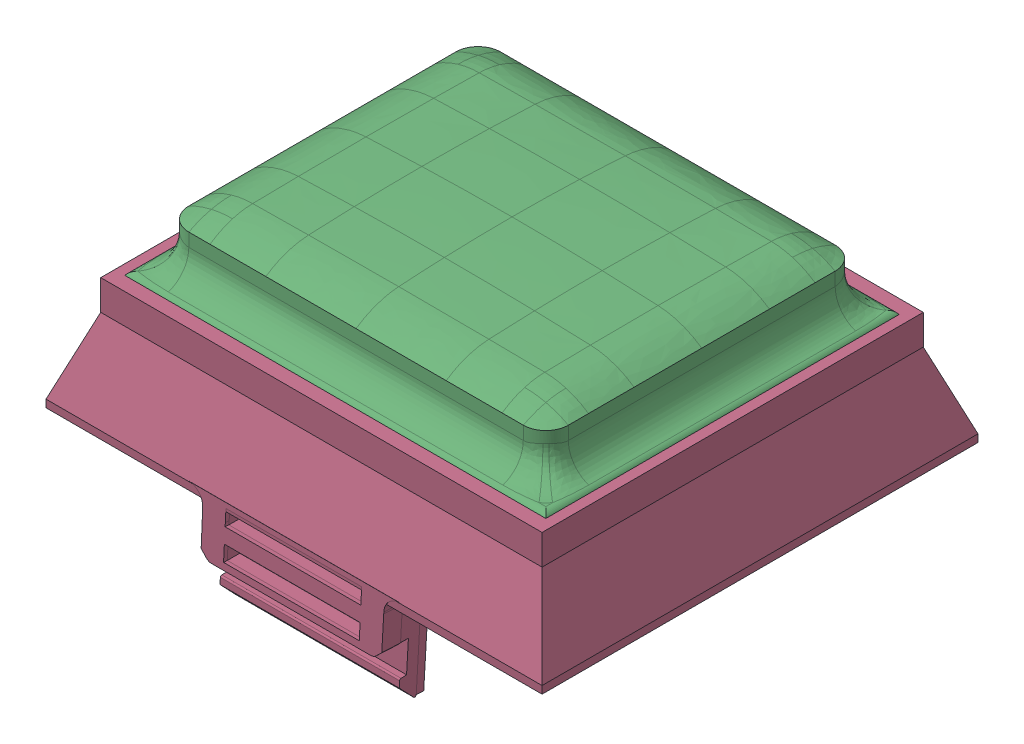
SolidWorks assembly BoardALL, configuration 默认. Lengths in mm.
Overall size (33 18.3 29.5).
5 component instances, 5 part files, 13 mates.
Components (placement in the parent):
- Boardlensall-1: Boardlensall [默认] at origin size (28.33 2.18 23.83)
- BoardInsideSkin-1: BoardInsideSkin [默认] at (0.0001 0 0.2499) size (23.8 5.48 19.29)
- BoardTopskin-1: BoardTopskin [默认] at (0.0001 2 0.2499) size (28.02 6.25 23.52)
- BoardSupportBase-2: BoardSupportBase [默认] at origin size (33 14.05 29.5)
- chessboard-1: chessboard [默认] at (-4.7946 23.7 -14.5409) x (1 0 0) z (0 -1 0) size (22.5 16.35 0.4)
Mates (geometry in assembly coordinates):
- 同心2: concentric anti-aligned: cylinder of BoardInsideSkin-1 through (10.8751 17.7531 8.6249) axis (0 1 0) radius 0.7; cylinder of Board3Con1612611OriginalSkin_TOP-1 through (10.8751 24 8.6249) axis (0 -1 0) radius 0.7
- 同心3: concentric anti-aligned: cylinder of BoardInsideSkin-1 through (10.8751 17.7531 -9.1251) axis (0 1 0) radius 0.7; cylinder of Board3Con1612611OriginalSkin_TOP-1 through (10.8751 24 -9.1251) axis (0 -1 0) radius 0.7
- 重合4: coincident aligned: plane of BoardInsideSkin-1 through (10.8751 19 -9.1251) normal (0 -1 0); plane of Board3Con1612611OriginalSkin_TOP-1 through (0.0001 19 0.2499) normal (0 -1 0)
- 重合6: coordinate: point of BoardSupportBase-2
- 重合7: coincident anti-aligned: plane of lensall-1 through (13.75 19 -11.5) normal (0.939693 0.34202 0); plane of BoardSupportBase-2 through (13.75 19 12.7803) normal (-0.939693 -0.34202 0)
- 同心5: concentric aligned: cylinder of lensall-1 through (13.3294 18.6938 -11.0794) axis (-0.323616 0.889126 0.323616) radius 0.5; cylinder of BoardSupportBase-2 through (10.7866 25.6801 -8.5366) axis (-0.323616 0.889126 0.323616) radius 0.5
- 重合8: coincident anti-aligned: plane of lensall-1 through (0 18 0) normal (0 -1 0); plane of BoardSupportBase-2 through (0 18 0) normal (0 1 0)
- 重合9: coincident anti-aligned: plane of lensall-1 through (0 19 0) normal (0 1 0); plane of Board3Con1612611OriginalSkin_TOP-1 through (0.0001 19 0.2499) normal (0 -1 0)
- 重合10: coincident anti-aligned: plane of Board3Con1612611OriginalSkin_TOP-1 through (0.0001 19 11.7499) normal (0 0 1); plane of BoardSupportBase-2 through (-13.5999 21 11.7499) normal (0 0 -1)
- 重合11: coincident anti-aligned: plane of Board3Con1612611OriginalSkin_TOP-1 through (14.0001 19 0.2499) normal (1 0 0); plane of BoardSupportBase-2 through (14.0001 21 11.7499) normal (-1 0 0)
- 宽度1: width aligned: plane of BoardInsideSkin-1 through (11.5751 17.7531 -9.1251) normal (1 0 0); plane of chessboard-1 through (-12.0749 17.7531 -9.1251) normal (-1 0 0); plane of BoardInsideSkin-1 through (11.0001 23.3 1.7749) normal (1 0 0); plane of chessboard-1 through (-11.4999 23.3 -2.3251) normal (-1 0 0)
- 宽度2: width aligned: plane of BoardInsideSkin-1 through (-11.3749 17.7531 -9.8251) normal (0 0 -1); plane of chessboard-1 through (-11.3749 17.7531 9.3249) normal (0 0 1); plane of BoardInsideSkin-1 through (-3.2999 23.3 -8.4251) normal (0 0 -1); plane of chessboard-1 through (-5.3499 23.3 7.9249) normal (0 0 1)
- 重合12: coincident aligned: line of BoardInsideSkin-1 through (-11.4999 23.7 5.8749) axis (0 0 -1); line of chessboard-1 through (-11.4999 23.7 5.8749) axis (0 0 -1)
